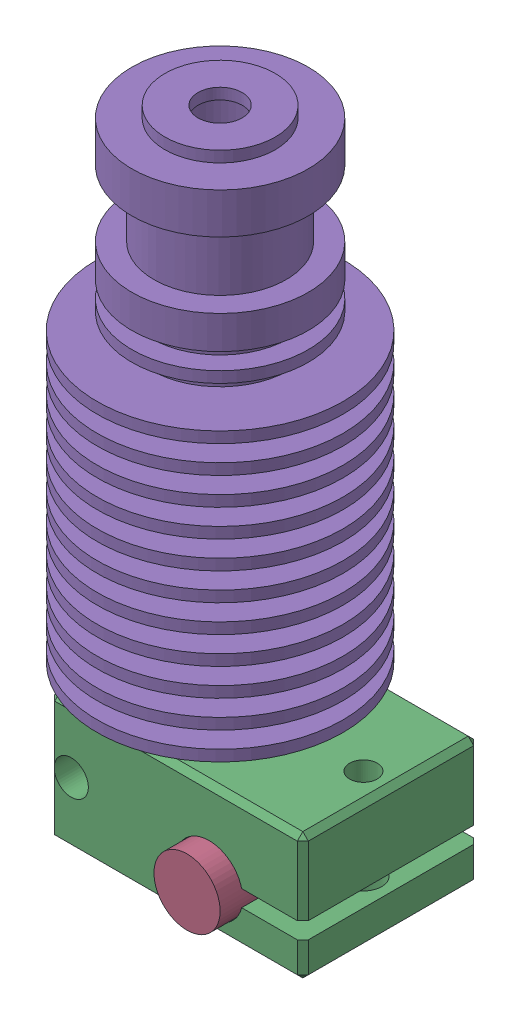
SolidWorks assembly E3D All Metal Hotend V7 v1, configuration Default. Lengths in mm.
Overall size (26.65 63.3 22.3).
5 component instances, 5 part files, 0 mates.
Components (placement in the parent):
- E3D v6 HotEnd - Heatbreak (1)-1: E3D v6 HotEnd - Heatbreak (1) [Default] at (0 -23.6743 -16.5743) x (-1 0 0) z (0 -1 0) size (7 7 21.9)
- E3D v6 HotEnd - Nozzle (1)-1: E3D v6 HotEnd - Nozzle (1) [Default] at (0 -34.1743 -16.5743) x (-0.866025 0 -0.5) z (0 -1 0) size (8.08 7 12.5)
- E3D v6 HotEnd - Heat Block (1)-1: E3D v6 HotEnd - Heat Block (1) [Default] at (15.5 -30.1743 -24.5743) x (-1 0 0) z (0 0 -1) size (23 11.5 16)
- Ceramic Cartridge Heater-1: Ceramic Cartridge Heater [Default] at (7 -26.1743 -26.5743) x (-1 0 0) z (0 0 -1) size (6 6 20)
- E3D v6 HotEnd - Heatsink (1) (1)-1: E3D v6 HotEnd - Heatsink (1) (1) [Default] at (0 -16.5743 -16.5743) x (-1 0 0) z (0 -1 0) size (22.3 22.3 43.7)
